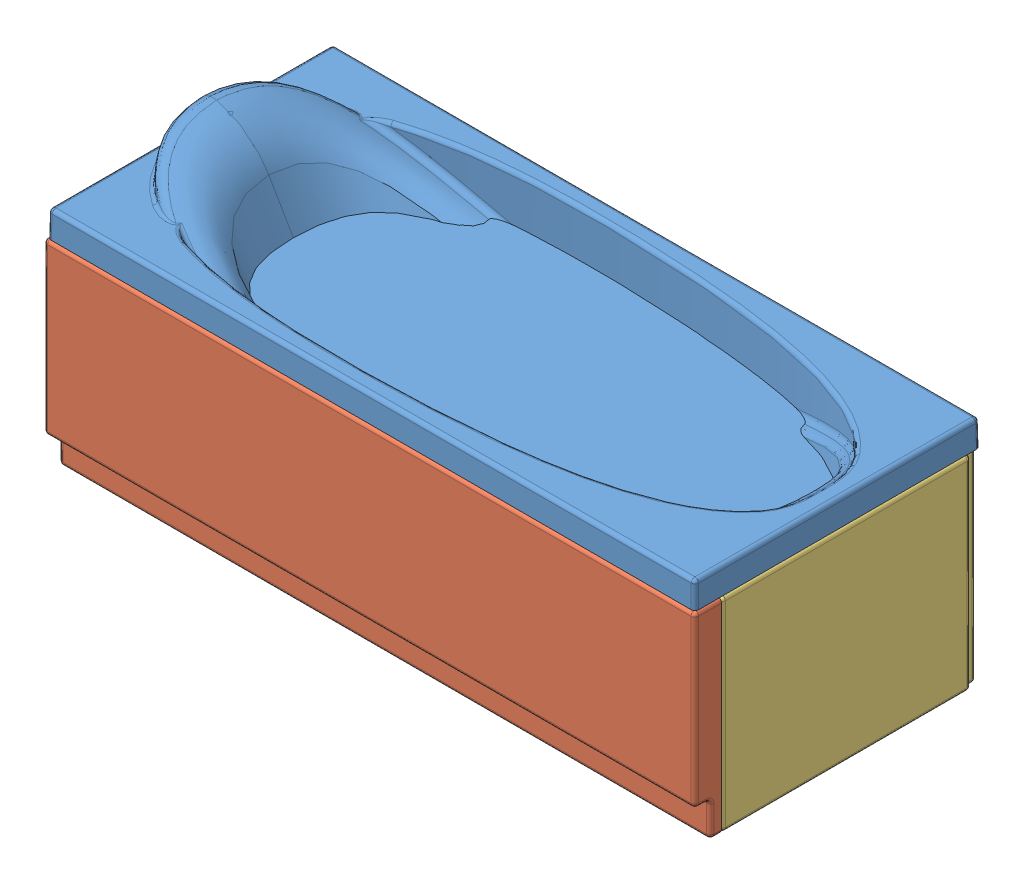
SolidWorks assembly Country 1701125, configuration По умолчанию. Lengths in mm.
Overall size (1710 700.98 754.32).
4 component instances, 3 part files, 9 mates.
Components (placement in the parent):
- Модель 1700x750-1: Модель 1700x750 [По умолчанию] at (0.7589 -260.3912 10.8316) size (1700.24 591.5 749.32)
- Копия Панель 1700-1: Копия Панель 1700 [По умолчанию] at (856.0456 -417.1269 325.5091) x (-1 0 0) z (0 0 -1) size (1710 550 70)
- Копия Панель боковая 750-1: Копия Панель боковая 750 [По умолчанию] at (829.0456 -137.1269 -6.9909) size (27 560 705)
- Копия Панель боковая 750-2: Копия Панель боковая 750 [По умолчанию] at (-826.9544 -137.1269 -6.9909) x (-1 0 0) z (0 0 -1) size (27 560 705)
Mates (geometry in assembly coordinates):
- Совпадение4: coincident anti-aligned: plane of Модель 1700x750-1 through (882.8592 117.8731 -389.0807) normal (0 -1 0); plane of Копия Панель 1700-1 through (-853.9544 117.8731 390.5091) normal (0 1 0)
- Расстояние1: distance = 5 mm: plane of Копия Панель 1700-1 through (-853.9544 132.8731 390.5091) normal (0 0 1); line of Модель 1700x750-1 through (841.2278 117.8731 385.5091) axis (-1 0 0)
- Ширина1: width anti-aligned: plane of Копия Панель 1700-1 through (856.0456 -417.1269 325.5091) normal (1 0 0); plane of Копия Панель 1700-1 through (-853.9544 -417.1269 325.5091) normal (-1 0 0); plane of Модель 1700x750-1 through (-855.666 -256.4269 392.0426) normal (-0.999845 0.017609 0); plane of Модель 1700x750-1 through (857.7572 -256.4269 392.0426) normal (0.999845 0.017609 0)
- Совпадение6: coincident aligned: plane of Копия Панель 1700-1 through (856.0456 -417.1269 325.5091) normal (1 0 0); plane of Копия Панель боковая 750-1 through (856.0456 117.8731 -334.4909) normal (1 0 0)
- Совпадение7: coincident aligned: plane of Копия Панель 1700-1 through (-853.9544 -417.1269 350.5091) normal (0 -1 0); plane of Копия Панель боковая 750-1 through (844.0456 -417.1269 -359.4909) normal (0 -1 0)
- Совпадение8: coincident: plane of Копия Панель 1700-1 through (826.0456 -317.1269 320.5091) normal (0 0 -1); line of Копия Панель боковая 750-1 through (846.0456 -407.1269 320.5091) axis (0 1 0)
- Совпадение9: coincident aligned: plane of Копия Панель боковая 750-2 through (-853.9544 117.8731 320.5091) normal (-1 0 0); plane of Копия Панель 1700-1 through (-853.9544 -417.1269 325.5091) normal (-1 0 0)
- Совпадение10: coincident aligned: plane of Копия Панель 1700-1 through (-853.9544 -417.1269 350.5091) normal (0 -1 0); plane of Копия Панель боковая 750-2 through (-841.9544 -417.1269 345.5091) normal (0 -1 0)
- Совпадение11: coincident: plane of Копия Панель 1700-1 through (826.0456 -317.1269 320.5091) normal (0 0 -1); line of Копия Панель боковая 750-2 through (-843.9544 107.8731 320.5091) axis (0 -1 0)
